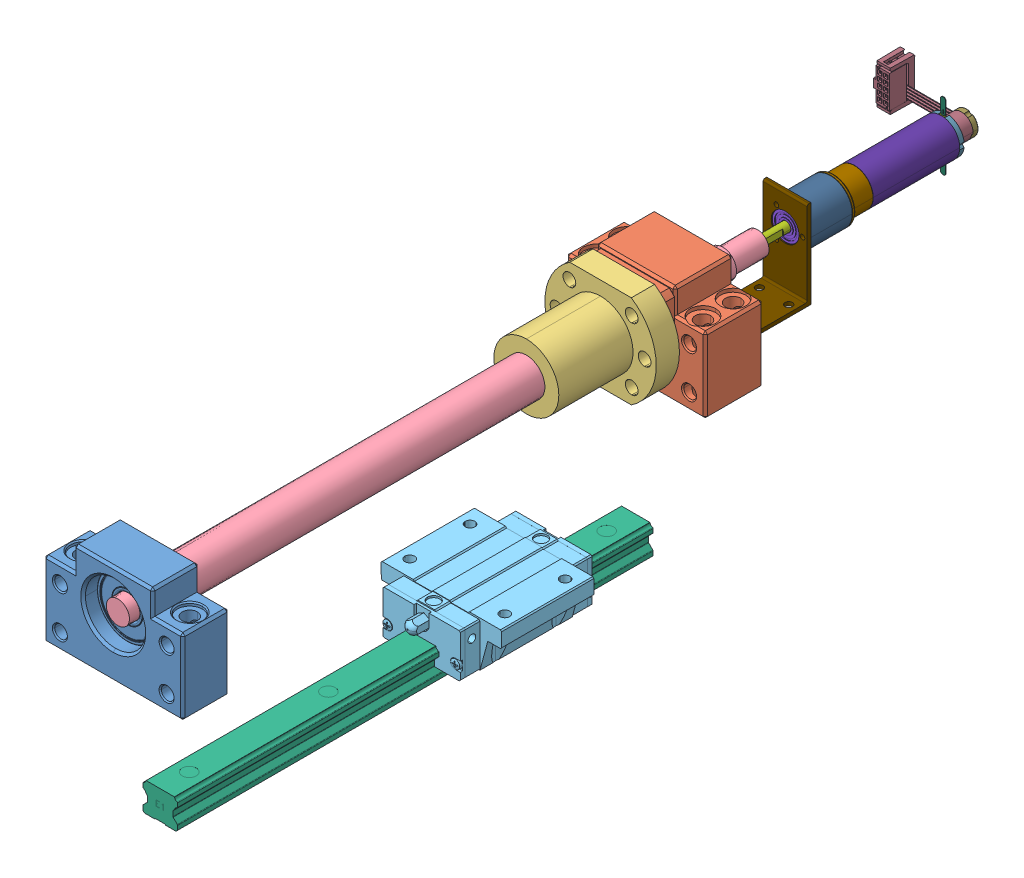
SolidWorks assembly ScrewAssembly_15cm_TOP, configuration Default. Lengths in mm.
Overall size (61 107.5 369.65).
19 component instances, 18 part files, 22 mates.
Components (placement in the parent):
- BF12.step-1: BF12.step [Default] at (-30 0 240.25) size (60 43 20)
- BK12.step-1: BK12.step [Default] at (-30 0 12.5) size (60 43 30.65)
- RM1605 Ball Nut STEP.step-1: RM1605 Ball Nut STEP.step [Default] at (-30 25 30.15) x (0 0 1) z (0 -1 0) size (42 48 40)
- RM1605-1: RM1605 [Smaller Versionn] at (-30 25 248.25) x (-0.470167 -0.882577 0) z (0 0 -1) size (16 16 275.75)
- Carriage-1: Carriage [Default] at (-30 -62.5 159.8307) x (1 0 0) z (0 1 0) size (52 63.99 19.5)
- Rail-1: Rail [Default] at (-30 -62.5 230) x (1 0 0) z (0 1 0) size (15 205 12.5)
- Gantry Motor.stp-1: Gantry Motor.stp [Default] at (-30 25 -41) x (0 0 -1) z (1 0 0) size (91.9 29 40.5)
  - 0.stp-1: 0.stp [Default] at origin size (14.5 4 4)
  - 0-0.stp-1: 0-0.stp [Default] at origin size (4 12 12)
  - 0-1.stp-1: 0-1.stp [Default] at origin size (10.45 19 19)
  - 0-2.stp-1: 0-2.stp [Default] at origin size (17.97 19 19)
  - 0-3.stp-1: 0-3.stp [Default] at origin size (0.5 9.2 9.2)
  - 0-4.stp-1: 0-4.stp [Default] at origin size (2.88 10 10)
  - 0-5.stp-1: 0-5.stp [Default] at origin size (10.9 17.48 36)
  - 0-6.stp-1: 0-6.stp [Default] at origin size (2 15.64 15.71)
  - 0-7.stp-1: 0-7.stp [Default] at origin size (2.2 29 2.3)
  - 0-8.stp-1: 0-8.stp [Default] at origin size (2.1 15.8 15.45)
  - 0-9.stp-1: 0-9.stp [Default] at origin size (37.3 16 16)
- Motor Mounting Bracket-1: Motor Mounting Bracket [8982K701] at (-20.5 0 -21.95) x (0 0 -1) z (1 0 0) size (38.1 38.1 19)
Mates (geometry in assembly coordinates):
- Coincident5: coincident: plane of assembly through (0 0 0) normal (0 1 0); plane of BK12.step-1 through (-60 0 25) normal (0 -1 0); plane of assembly
- Coincident6: coincident: plane of assembly through (0 0 0) normal (0 1 0); plane of BF12.step-1 through (-60 0 250.25) normal (0 -1 0); plane of assembly
- Coincident7: coincident: plane of assembly through (0 0 0) normal (0 0 1); plane of BK12.step-1 through (-60 0 0) normal (0 0 -1); plane of assembly
- Coincident8: coincident: plane of assembly through (0 0 0) normal (1 0 0); plane of BK12.step-1 through (0 0 25) normal (1 0 0); plane of assembly
- Concentric7: concentric: cylinder of RM1605 Ball Nut STEP.step-1 through (-30 25 30.15) axis (0 0 1) radius 8; cylinder of RM1605-1 through (-30 25 167.3246) axis (0 0 1) radius 8
- Coincident10: coincident: plane of BK12.step-1 through (-30 32.65 26.5) normal (0 0 1); plane of RM1605-1 through (-35.2955 27.821 26.5) normal (0 0 -1)
- Concentric8: concentric: cylinder of BK12.step-1 through (-30 25 47.8429) axis (0 0 1) radius 6; cylinder of RM1605-1 through (-30 25 167.3246) axis (0 0 1) radius 8
- Concentric9: concentric: cylinder of BF12.step-1 through (-30 25 244.456) axis (0 0 1) radius 5; cylinder of RM1605-1 through (-30 25 167.3246) axis (0 0 1) radius 8
- Coincident11: coincident: plane of BF12.step-1 through (-30 30 236.25) normal (0 0 -1); plane of RM1605-1 through (-37.0606 28.7613 236.25) normal (0 0 1)
- Coincident21: coincident: plane of BK12.step-1 through (-60 0 25) normal (0 0 1); plane of Rail-1 through (-30 -56.3514 25) normal (0 0 -1)
- Width1: width anti-aligned: plane of Carriage-1 through (-22.5 -52.4 45.1497) normal (-1 0 0); plane of Rail-1 through (-37.5 -52.4 45.1497) normal (1 0 0); plane of Carriage-1 through (-22.5 -52.4 25) normal (1 0 0); plane of Rail-1 through (-37.5 -52.4 25) normal (-1 0 0)
- Coincident22: coincident anti-aligned: plane of Carriage-1 through (-30 -50 45.1497) normal (0 -1 0); plane of Rail-1 through (-30 -50 25) normal (0 1 0)
- Width2: width: plane of BK12.step-1 through (0 0 25) normal (1 0 0); plane of Carriage-1 through (-60 32.5 25) normal (-1 0 0); plane of BK12.step-1 through (-56 -41.5 88.9297) normal (-1 0 0); plane of Carriage-1 through (-4 -42 69.0297) normal (1 0 0)
- Coincident25: coincident: plane of BK12.step-1 through (-42 25 30.15) normal (0 0 1); plane of RM1605 Ball Nut STEP.step-1 through (-30 25 30.15) normal (0 0 -1)
- Distance1: distance = 63.5 mm: cylinder of RM1605 Ball Nut STEP.step-1 through (-30 25 72.15) axis (0 0 -1) radius 14; plane of Carriage-1 through (-30 -38.5 69.0297) normal (0 1 0)
- Concentric10: concentric aligned: cylinder of RM1605-1 through (-30 25 167.3246) axis (0 0 1) radius 8; cylinder of Gantry Motor.stp-1/0.stp-1 through (-30 25 -34.75) axis (0 0 1) radius 2
- Parallel1: parallel: plane of BK12.step-1 through (-60 32.5 25) normal (-1 0 0); plane of Gantry Motor.stp-1/0-5.stp-1 through (-60 21.83 -115.7) normal (-1 0 0)
- Coincident26: coincident anti-aligned: plane of RM1605-1 through (-30 25 -27.5) normal (0 0 -1); plane of Gantry Motor.stp-1/0.stp-1 through (-30 25 -27.5) normal (0 0 1)
- Coincident27: coincident anti-aligned: plane of Gantry Motor.stp-1/0-2.stp-1 through (-22.25 25 -41) normal (0 0 1); plane of Motor Mounting Bracket-1 through (-39.5 0 -41) normal (0 0 -1)
- Concentric11: concentric aligned: cylinder of Gantry Motor.stp-1/0-0.stp-1 through (-30 25 -41.75) axis (0 0 -1) radius 6; cylinder of Motor Mounting Bracket-1 through (-30 25 -2.899) axis (0 0 -1) radius 5.9995
- Coincident28: coincident: plane of BK12.step-1 through (-60 0 25) normal (0 -1 0); plane of Motor Mounting Bracket-1 through (-39.5 0 -2.9) normal (0 -1 0)
- Distance2: distance = 83.5 mm: point of Carriage-1
